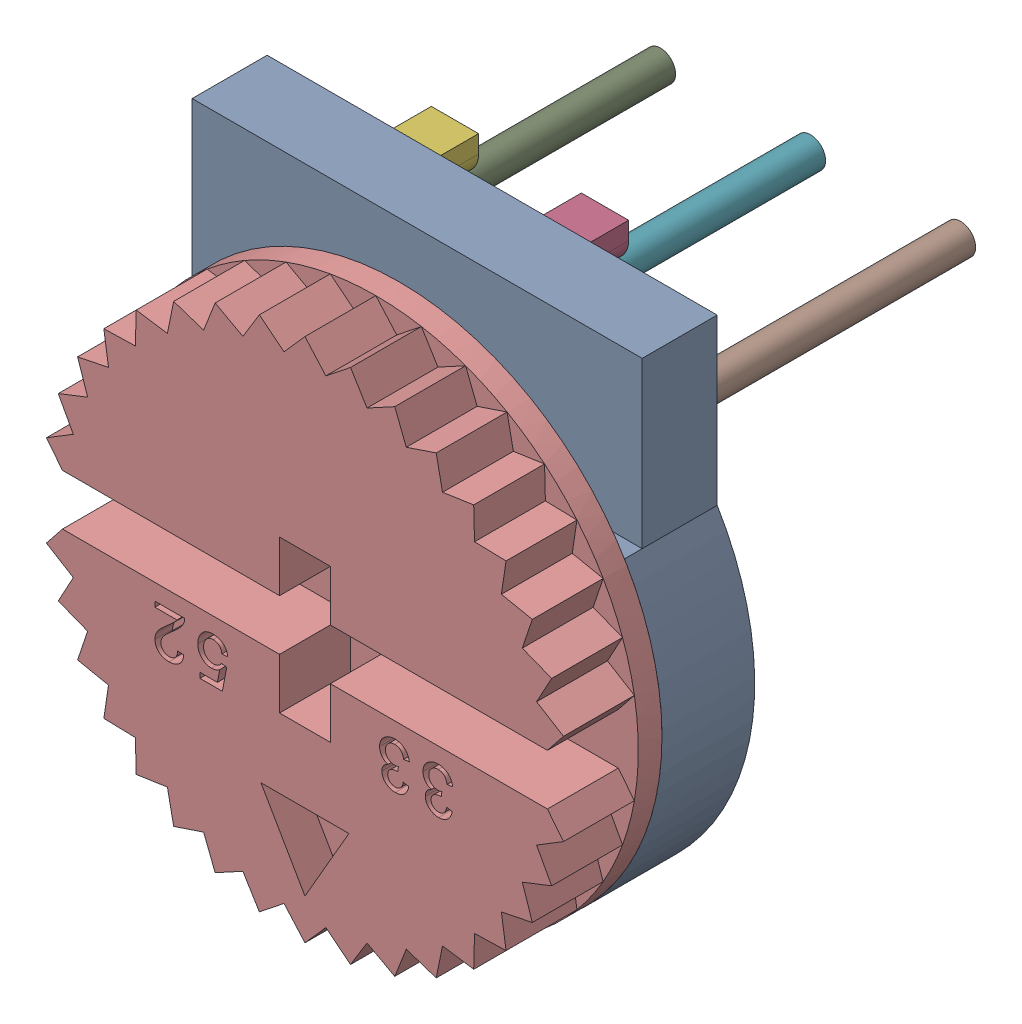
SolidWorks assembly R33, configuration Default. Lengths in mm.
Overall size (8.89 9.53 8.56).
11 component instances, 10 part files, 0 mates.
Components (placement in the parent):
- 3352T-1: 3352T [Default] at (14.6048 2.4638 0) x (-1 0 0) z (0 1 0) size (8.89 8.56 9.53)
  - 3352T_1-1: 3352T_1 [Default] at origin size (8.89 1.57 9.53)
  - 3352T_2-1: 3352T_2 [Default] at origin size (2 0.64 2)
  - 3352T_3-1: 3352T_3 [Default] at origin size (0.87 0.64 0.76)
  - 3352T_4-1: 3352T_4 [Default] at origin size (0.8 0.64 0.7)
  - 3352T_5-1: 3352T_5 [Default] at origin size (0.87 0.64 0.76)
  - 3352T_6-1: 3352T_6 [Default] at origin size (0.8 0.64 0.7)
  - 3352T_7-1: 3352T_7 [Default] at origin size (0.51 5.39 0.51)
  - 3352T_8-1: 3352T_8 [Default] at origin size (0.51 5.39 0.51)
  - 3352T_9-1: 3352T_9 [Default] at origin size (0.51 5.39 0.51)
  - 3352T_10-1: 3352T_10 [Default] at origin size (8.89 1.6 8.89)
